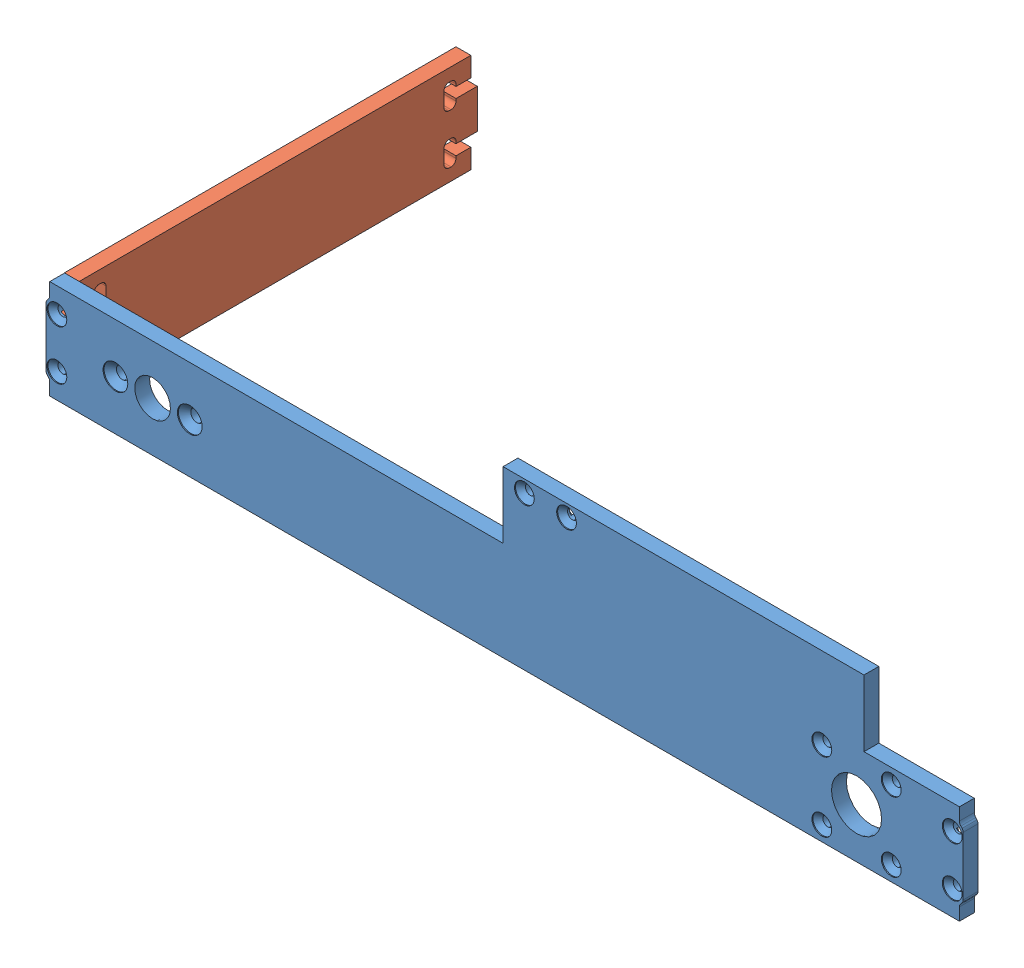
SolidWorks assembly tap-test, configuration Default. Lengths in mm.
Overall size (185 33.4 83.3).
2 component instances, 2 part files, 3 mates.
Components (placement in the parent):
- frame-side-1: frame-side [Default] at origin size (185 33.4 3)
- frame-end-1: frame-end [Default] at (-88.8 0 -42.5) x (0 0 1) z (-1 0 0) size (81.6 20 3)
Mates (geometry in assembly coordinates):
- Coincident1: coincident: plane of frame-side-1 through (0 0 -3) normal (0 0 -1); plane of frame-end-1 through (-91.8 0 -3) normal (0 0 1)
- Concentric1: concentric: cylinder of frame-side-1 through (-90.3 5 -3.001) axis (0 0 1) radius 1; line of frame-end-1 through (-90.3 5 -96.2846) axis (0 0 1)
- Concentric2: concentric: cylinder of frame-side-1 through (-90.3 -5 -3.001) axis (0 0 1) radius 1; line of frame-end-1 through (-90.3 -5 -96.7844) axis (0 0 1)
